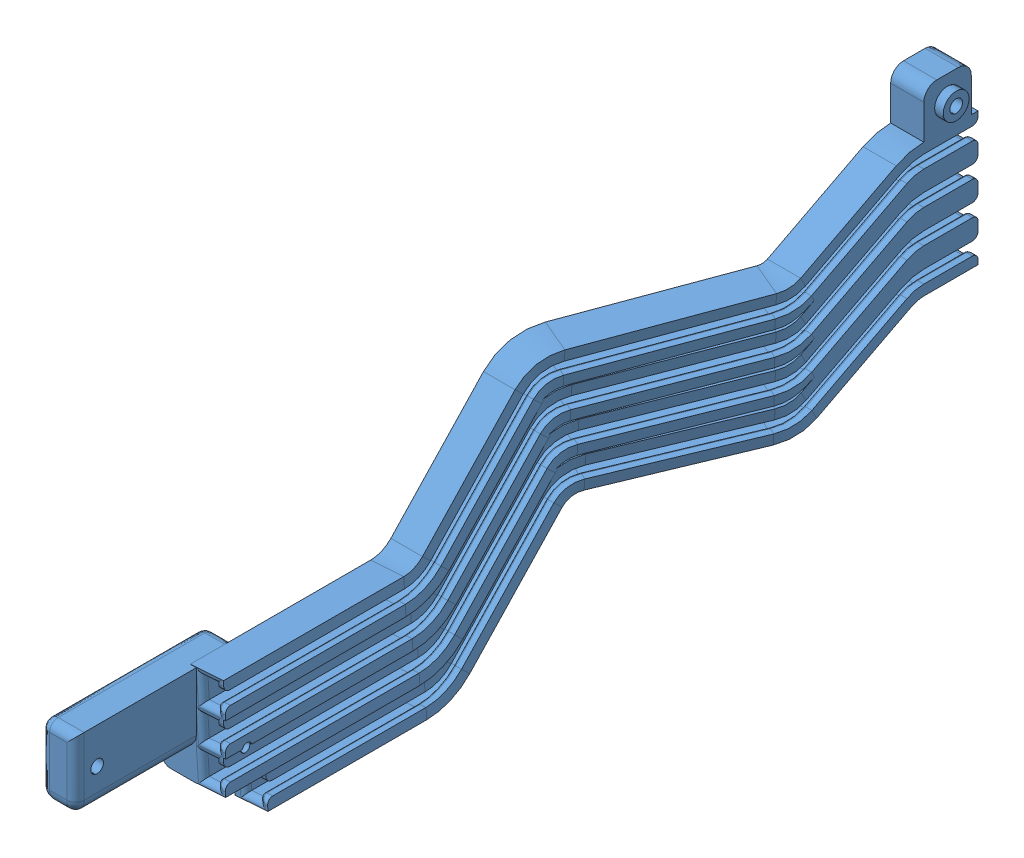
SolidWorks assembly cSL cap guide S4, configuration Default. Lengths in mm.
Overall size (32.46 85.55 186.8).
5 component instances, 2 part files, 4 mates.
Components (placement in the parent):
- cSL cap guides-1: cSL cap guides [41] at origin size (23.85 51.41 158.8) (hidden)
- cSL cap guides-2: cSL cap guides [42] at origin size (23.86 51.43 158.8) (hidden)
- cSL cap guides-3: cSL cap guides [43] at origin size (23.87 51.44 158.8) (hidden)
- cSL cap guides-4: cSL cap guides [44] at origin size (23.88 51.45 149) (hidden)
- cSL cap guide S4^cSL cap guide S4-1: cSL cap guide S4^cSL cap guide S4 [Default] at (-35.6 0 0) x (0 0 -1) z (1 0 0) size (186.8 85.55 32.46) (virtual)
Mates (geometry in assembly coordinates):
- InPlace1: in place: plane of ? through (-35.6 133.6 -652.4384) normal (1 0 0); plane of cSL cap guide S4^cSL cap guide S4-1 through (-35.6 0 0) normal (1 0 0); moOrthogonalPlaneRef_w of ? through (-35.6 133.6 -652.4384) normal (1 0 0); line of cSL cap guide S4^cSL cap guide S4-1 through (-55 -35.6 0) axis (0 0 1); plane of ? through (-35.6 133.6 -652.4384) normal (1 0 0); plane of cSL cap guide S4^cSL cap guide S4-1 through (-35.6 0 0) normal (0 0 -1); plane of ? through (-35.6 133.6 -652.4384) normal (1 0 0); unknown of cSL cap guide S4^cSL cap guide S4-1
- Coincident1: coincident aligned: plane of cSL cap guides-1; plane of cSL cap guide S4^cSL cap guide S4-1
- Coincident2: coincident aligned: moOrthogonalPlaneRef_w of cSL cap guides-1 through (-35.6 0 0) normal (0 1 0); plane of cSL cap guide S4^cSL cap guide S4-1
- Coincident3: coincident anti-aligned: moOrthogonalPlaneRef_w of cSL cap guides-1 through (-35.6 0 0) normal (0 0 1); plane of cSL cap guide S4^cSL cap guide S4-1 through (-35.6 0 0) normal (0 0 -1)
